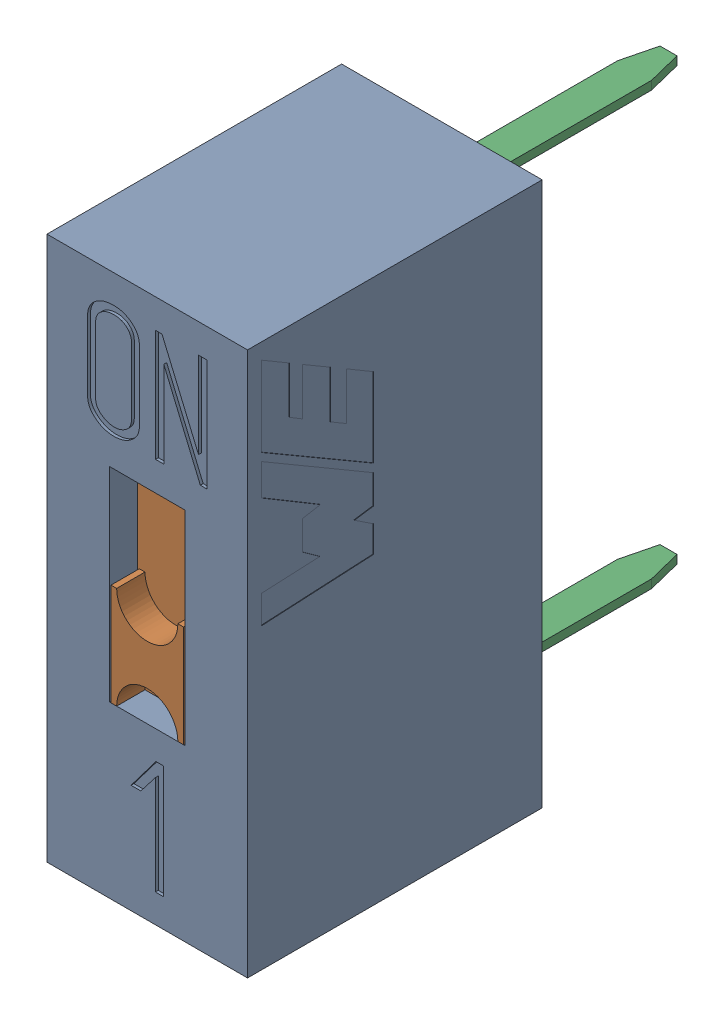
SolidWorks assembly 418117170901, configuration Default. Lengths in mm.
Overall size (3.54 9.6 9.2).
3 component instances, 3 part files, 0 mates.
Components (placement in the parent):
- Base_switch-1: Base_switch [Default] at origin size (3.54 9.6 5.2)
- clip-1: clip [Default] at (0 -0.9 4.7) size (2.3 5.8 2.9)
- base-1: base [Default] at (0 0 0.2) size (2.54 8.7 6.2)
